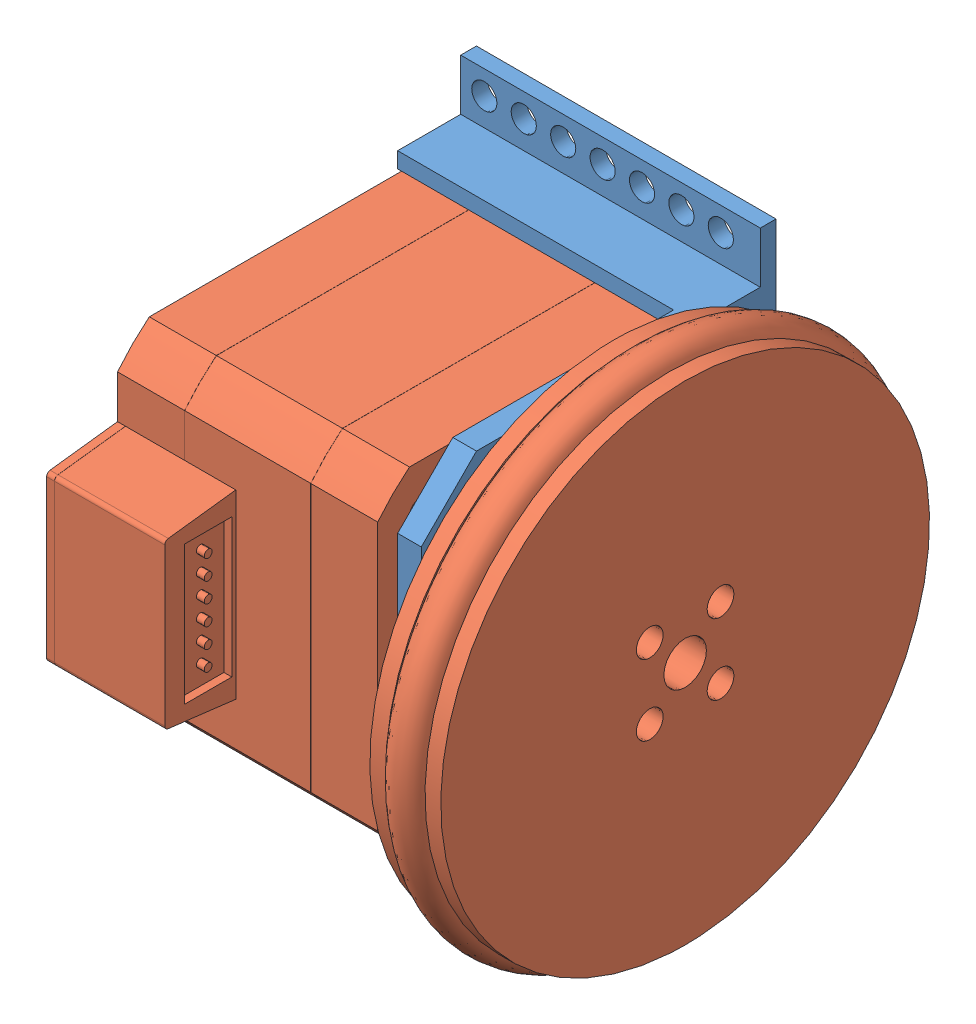
SolidWorks assembly rumba_moter_wheel, configuration ﾃﾞﾌｫﾙﾄ. Lengths in mm.
Overall size (51.5 65 65).
2 component instances, 2 part files, 3 mates.
Components (placement in the parent):
- mount.stp-1: mount.stp [ﾃﾞﾌｫﾙﾄ] at (8.4385 13.2505 38.5019) size (38 61 45)
- stepper (1).stp-1: stepper (1).stp [ﾃﾞﾌｫﾙﾄ] at (16.9385 14.2505 42.5313) size (51 65 65)
Mates (geometry in assembly coordinates):
- 一致1: coincident anti-aligned: plane of mount.stp-1 through (11.4385 25.2505 42.5313) normal (0 0 1); plane of stepper (1).stp-1 through (-23.0615 -11.7201 42.5313) normal (0 0 -1)
- 一致2: coincident anti-aligned: plane of mount.stp-1 through (-8.0615 26.2505 59.5019) normal (0 -1 0); plane of stepper (1).stp-1 through (-23.0615 26.2505 46.5608) normal (0 1 0)
- 一致3: coincident anti-aligned: plane of mount.stp-1 through (11.4385 4.2505 59.5019) normal (-1 0 0); plane of stepper (1).stp-1 through (11.4385 5.2505 52.5313) normal (1 0 0)
